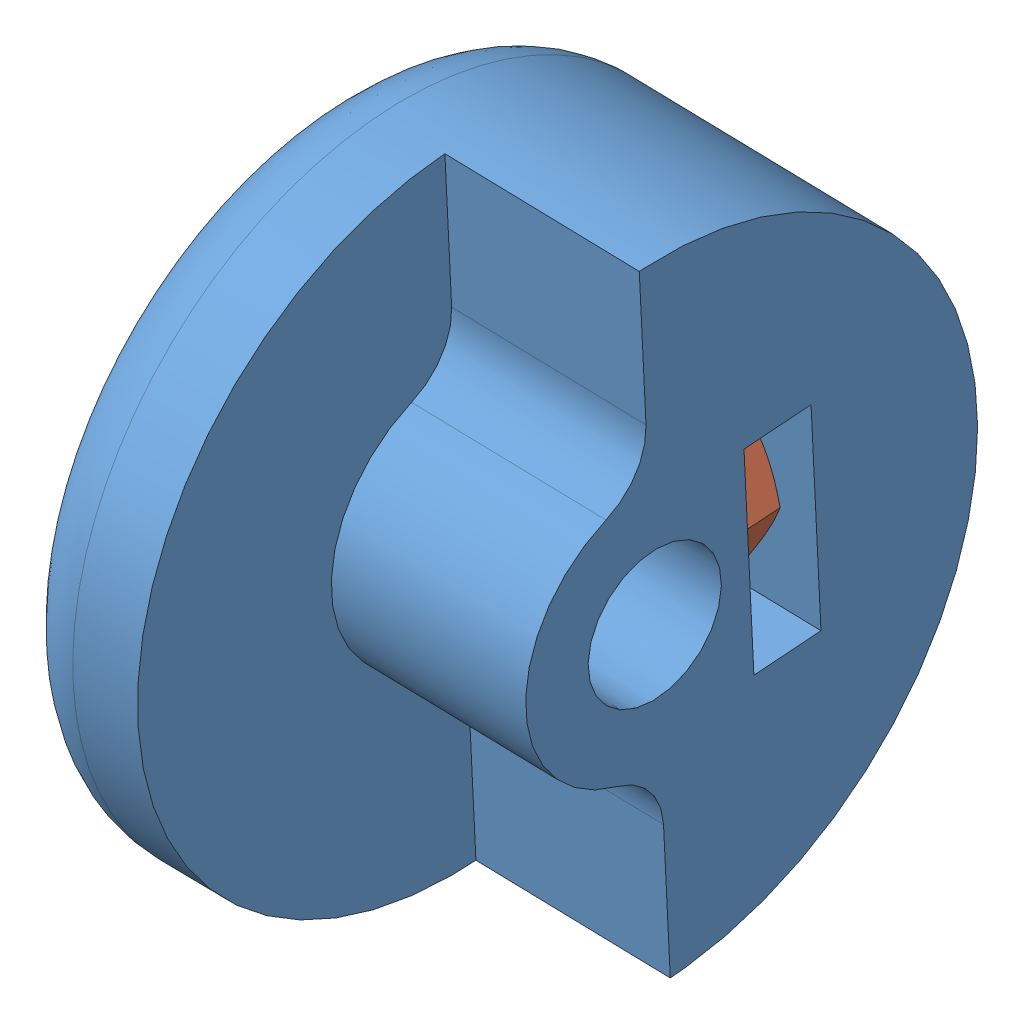
SolidWorks assembly DISP_Button_Head, configuration Default. Lengths in mm.
Overall size (16.73 32.11 31.89).
3 component instances, 3 part files, 5 mates.
Components (placement in the parent):
- DISP_Button_Head-1: DISP_Button_Head [Default] at origin size (16.73 32.11 31.89)
- 90480A009 - NUT, 8-32, STEEL-1: 90480A009 - NUT, 8-32, STEEL [90480A009] at (326.9082 6184.0708 3260.9167) x (-0.026875 -0.996836 -0.074802) z (0.999639 -0.0268 -0.002011) size (8.73 3.79 10.08)
- 92311A189 - SCREW, SET, 8-32 X .1875, CUP POINT, HEX DRIVE, 18-8-1: 92311A189 - SCREW, SET, 8-32 X .1875, CUP POINT, HEX DRIVE, 18-8 [92311A189] at (326.9082 6184.037 3261.3663) x (-0.906998 -0.419955 -0.031513) z (0 0.074829 -0.997196) size (4.2 4.28 5.07)
Mates (geometry in assembly coordinates):
- Concentric1: concentric: cylinder of DISP_Button_Head-1 through (326.9082 6183.6004 3267.1855) axis (0 -0.074829 0.997196) radius 2.2479; circle of 90480A009 - NUT, 8-32, STEEL-1
- Parallel1: parallel: plane of DISP_Button_Head-1 through (323.8397 6178.9619 3262.1889) normal (0.87915 0.475209 0.035659); plane of 90480A009 - NUT, 8-32, STEEL-1 through (324.2712 6181.0521 3243.7294) normal (-0.87915 -0.475209 -0.035659)
- Width1: width anti-aligned: plane of DISP_Button_Head-1 through (0 -208.8234 2782.854) normal (0 0.074829 -0.997196); plane of DISP_Button_Head-1 through (333.3634 6188.012 3259.5568) normal (0 -0.074829 0.997196); plane of 90480A009 - NUT, 8-32, STEEL-1 through (324.5059 6188.3713 3262.8313) normal (0 -0.074829 0.997196); plane of 90480A009 - NUT, 8-32, STEEL-1 through (324.5059 6188.6089 3259.6652) normal (0 0.074829 -0.997196)
- Concentric2: concentric: cylinder of DISP_Button_Head-1 through (326.9082 6183.6004 3267.1855) axis (0 -0.074829 0.997196) radius 2.2479; cone of 92311A189 - SCREW, SET, 8-32 X .1875, CUP POINT, HEX DRIVE, 18-8-1 through (326.2525 6183.809 3258.4856) axis (0 -0.074829 0.997196)
- Coincident1: coincident aligned: plane of 90480A009 - NUT, 8-32, STEEL-1 through (324.5059 6188.6089 3259.6652) normal (0 0.074829 -0.997196); plane of 92311A189 - SCREW, SET, 8-32 X .1875, CUP POINT, HEX DRIVE, 18-8-1 through (326.9082 6184.1896 3259.3336) normal (0 0.074829 -0.997196)
